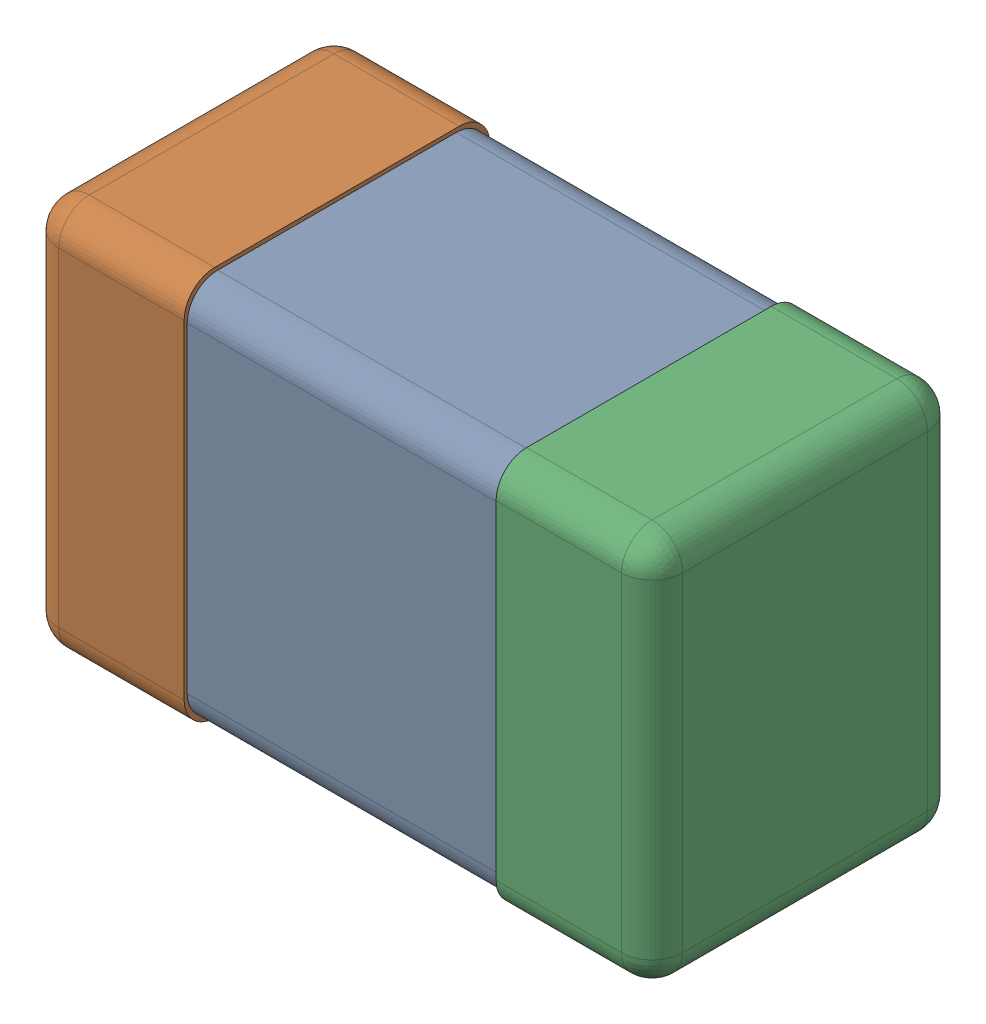
SolidWorks assembly C1, configuration Predeterminado. Lengths in mm.
Overall size (2 1.25 0.98).
4 component instances, 3 part files, 0 mates.
Components (placement in the parent):
- 6074688640-1: 6074688640 [Predeterminado] at (28 46 0) x (-1 0 0) z (0 0 1) size (2 1.25 0.98)
  - body2-1: body2 [Predeterminado] at origin size (1 1.22 0.96)
  - Fillet2-1: Fillet2 [Predeterminado] at origin size (0.5 1.25 0.98)
  - Fillet1-1: Fillet1 [Predeterminado] at origin size (0.5 1.25 0.98)
